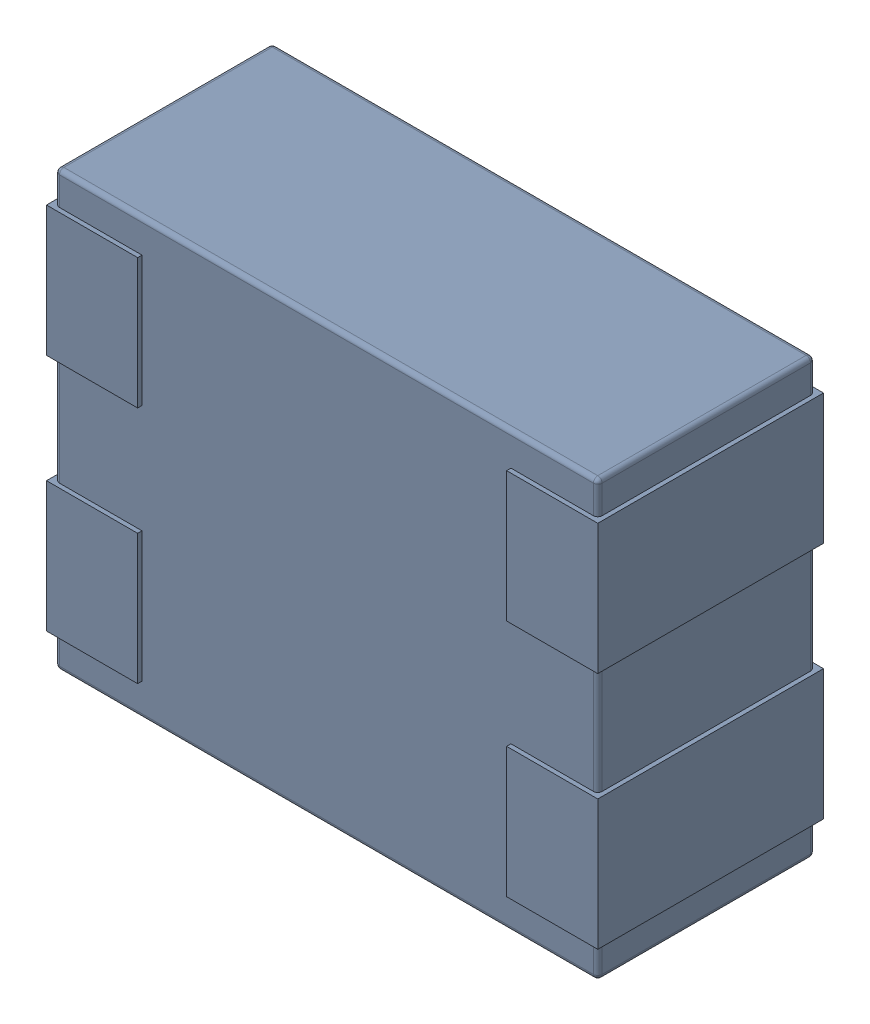
SolidWorks assembly L14, configuration Défaut. Lengths in mm.
Overall size (1.27 1 0.52).
4 component instances, 1 part files, 0 mates.
Components (placement in the parent):
- MCZ1210DH900L2TA0G-1: MCZ1210DH900L2TA0G [Défaut] at (76.7165 -28.046 -1.6) x (0 -1 0) z (0 0 1) size (1 1.27 0.52)
  - 3D_PCB1_2021-12-30 (1).step-1: 3D_PCB1_2021-12-30 (1).step [Défaut] at origin size (1 1.27 0.52)
    - a3ec64f90eb5404ebd79eca0046a794a.step-1: a3ec64f90eb5404ebd79eca0046a794a.step [Défaut] at (5.0419 -6.8961 1.6) size (1 1.27 0.52)
      - SOLID.step_650-1: SOLID.step_650 [Défaut] at origin size (1 1.27 0.52)
